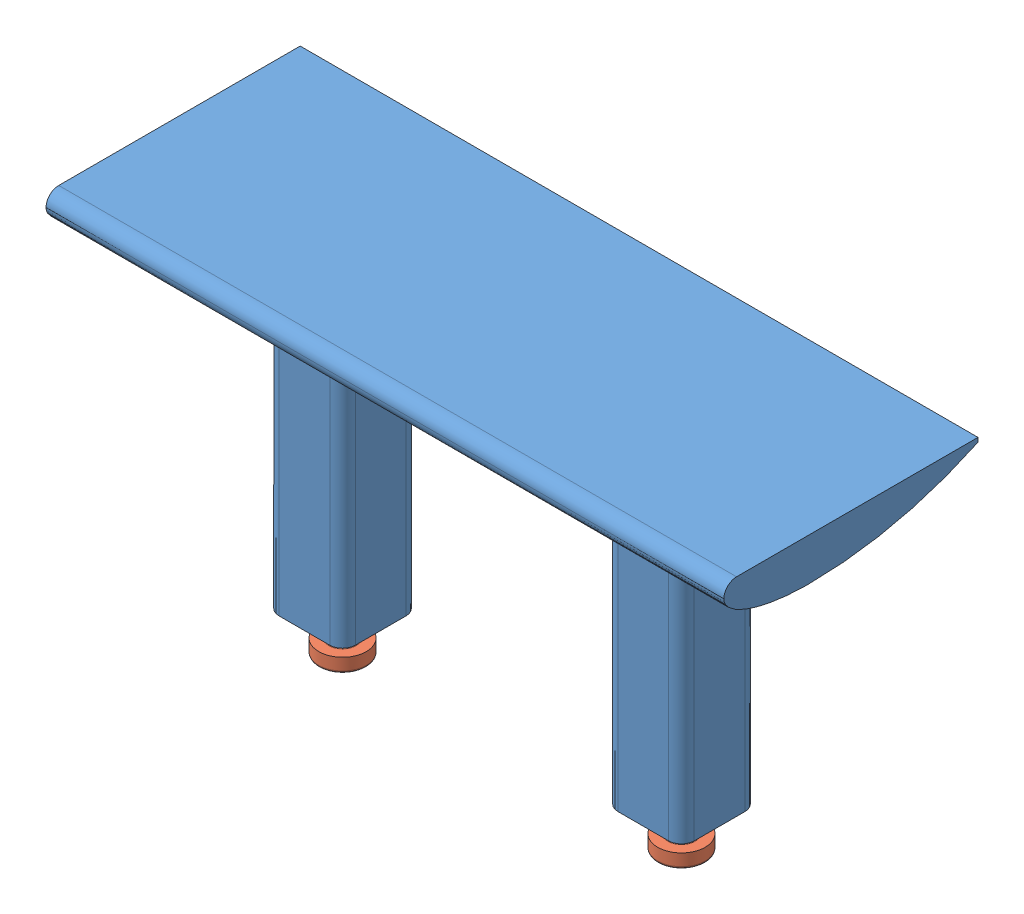
SolidWorks assembly Assembly spoiler, configuration Default. Lengths in mm.
Overall size (80 45.35 30).
3 component instances, 2 part files, 8 mates.
Components (placement in the parent):
- Spoiler-1: Spoiler [Default] at (0 40 0) x (1 0 0) z (0 0 -1) size (80 40 30)
- pan head cross recess screw_iso-1: pan head cross recess screw_iso [ISO 7045 - M3 x 10 - Z - 10N] at (20 -5.4 0) x (0 1 0) z (-1 0 0) size (12.35 5.6 5.6)
- pan head cross recess screw_iso-2: pan head cross recess screw_iso [ISO 7045 - M3 x 10 - Z - 10N] at (-20 -5.4 0) x (0 1 0) z (-1 0 0) size (12.35 5.6 5.6)
Mates (geometry in assembly coordinates):
- Coincident1: coincident aligned: plane of Spoiler-1 through (0 40 0) normal (1 0 0)
- Coincident2: coincident anti-aligned: plane of Spoiler-1 through (0 0 0) normal (0 -1 0)
- Coincident3: coincident anti-aligned: plane of Spoiler-1 through (0 40 0) normal (0 0 -1)
- Coincident4: coincident aligned: plane of pan head cross recess screw_iso-1 through (20 -3 -1.5) normal (0 1 0); plane of pan head cross recess screw_iso-2 through (-20 -3 -1.5) normal (0 1 0)
- Coincident5: coincident aligned: plane of pan head cross recess screw_iso-1 through (20.5275 -3.65 0.37) normal (0 0 -1); plane of pan head cross recess screw_iso-2 through (-19.4725 -3.65 0.37) normal (0 0 -1)
- Concentric1: concentric aligned: cylinder of Spoiler-1 through (20 10 0) axis (0 -1 0) radius 1.25; cylinder of pan head cross recess screw_iso-1 through (20 -30.8 0) axis (0 -1 0) radius 1.5
- Concentric2: concentric aligned: cylinder of Spoiler-1 through (-20 10 0) axis (0 -1 0) radius 1.25; cylinder of pan head cross recess screw_iso-2 through (-20 -30.8 0) axis (0 -1 0) radius 1.5
- Distance1: distance = 3 mm anti-aligned: plane of pan head cross recess screw_iso-2 through (-20 -3 -1.5) normal (0 1 0); plane of Spoiler-1 through (0 0 0) normal (0 -1 0)
